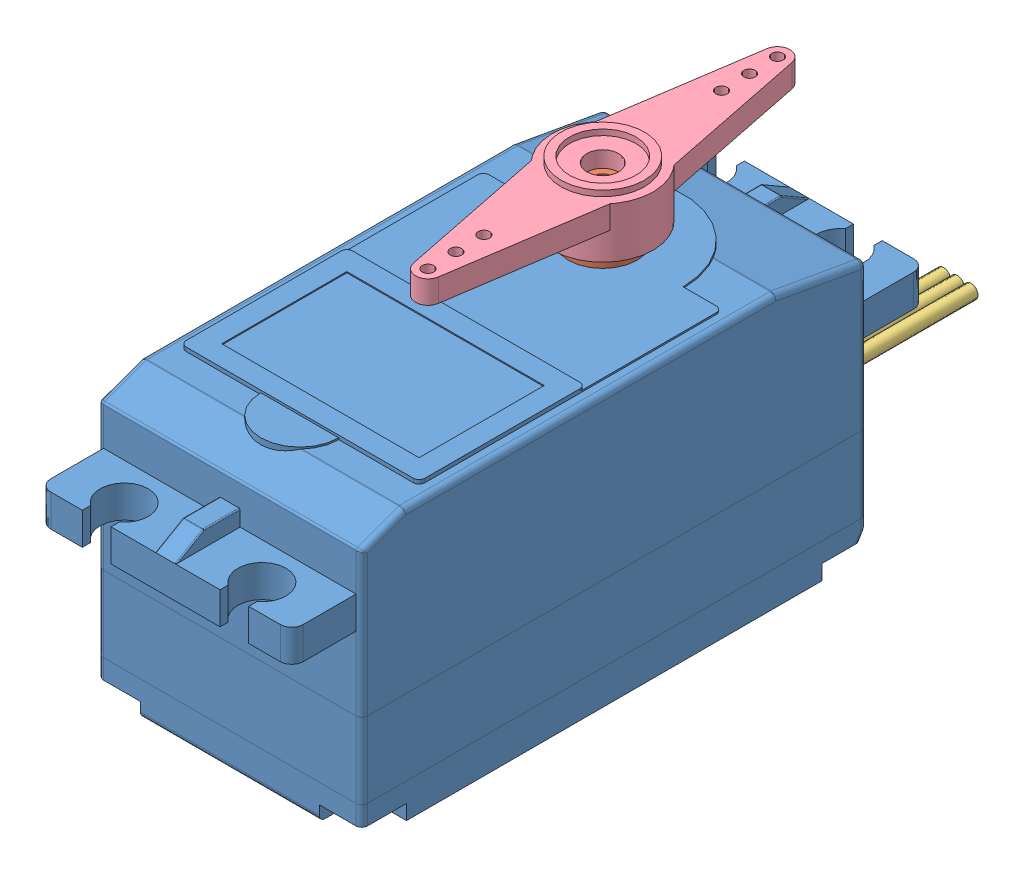
SolidWorks assembly Assembly_Servo_SDS-S0070, configuration Default. Lengths in mm.
Overall size (23 30.1 69).
4 component instances, 4 part files, 9 mates.
Components (placement in the parent):
- Servo_SDS-S0070_Body-1: Servo_SDS-S0070_Body [Default] at origin size (23 23.94 55.2)
- Servo_SDS-S0070_Shaft-1: Servo_SDS-S0070_Shaft [Default] at (0 0 -10.5) x (0.999694 0 -0.024727) z (0.024727 0 0.999694) size (5.8 18.6 5.8)
- Servo_SDS-S0070_Connector-2: Servo_SDS-S0070_Connector [Default] at (0 -4.55 -22) x (-1 0 0) z (0 0 -1) size (6.8 4.1 19.4)
- Servo_SDS-S0070_Horn-1: Servo_SDS-S0070_Horn [Default] at (0 15.6 -10.5) x (-0.999694 0 0.024727) z (-0.024727 0 -0.999694) size (8.8 4.9 33.4)
Mates (geometry in assembly coordinates):
- Coincident1: coordinate: point of Servo_SDS-S0070_Body-1; point of assembly
- Concentric1: concentric anti-aligned: cylinder of Servo_SDS-S0070_Body-1 through (0 -9.601 -10.5) axis (0 1 0) radius 3; cylinder of Servo_SDS-S0070_Shaft-1 through (0 14.6 -10.5) axis (0 -1 0) radius 2.9
- Coincident2: coincident anti-aligned: plane of Servo_SDS-S0070_Body-1 through (0 0 0) normal (0 1 0); plane of Servo_SDS-S0070_Shaft-1 through (0 0 -10.5) normal (0 -1 0)
- Coincident5: coincident anti-aligned: plane of Servo_SDS-S0070_Body-1 through (-11.5 -6.6 -22) normal (0 0 -1); plane of Servo_SDS-S0070_Connector-2 through (0 -4.55 -22) normal (0 0 1)
- Coincident6: coincident anti-aligned: plane of Servo_SDS-S0070_Connector-2 through (0 -4.55 -22) normal (-1 0 0); plane of assembly through (0 0 0) normal (1 0 0)
- Coincident7: coincident: line of Servo_SDS-S0070_Body-1 through (-11 -6.6 -22) axis (1 0 0); plane of Servo_SDS-S0070_Connector-2 through (3.4 -6.6 -23.4) normal (0 -1 0)
- Concentric2: concentric aligned: cylinder of Servo_SDS-S0070_Shaft-1 through (0 14.6 -10.5) axis (0 1 0) radius 0.8; cylinder of Servo_SDS-S0070_Horn-1 through (0 15.6 -10.5) axis (0 1 0) radius 1.39
- Coincident8: coincident anti-aligned: plane of Servo_SDS-S0070_Shaft-1 through (0 18.6 -10.5) normal (0 1 0); plane of Servo_SDS-S0070_Horn-1 through (0 18.6 -10.5) normal (0 -1 0)
- Coincident9: coincident anti-aligned: plane of Servo_SDS-S0070_Shaft-1 through (0 0 -10.5) normal (0.999694 0 -0.024727); plane of Servo_SDS-S0070_Horn-1 through (0 15.6 -10.5) normal (-0.999694 0 0.024727)
